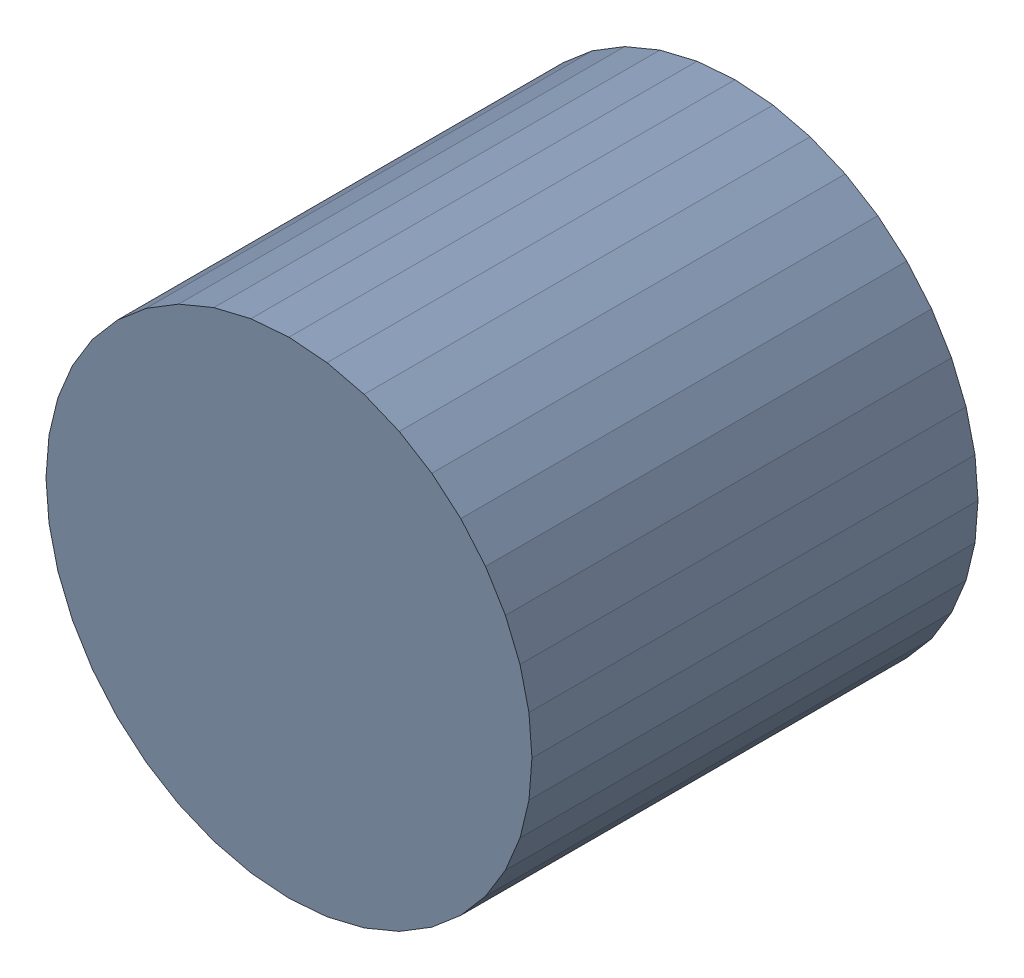
SolidWorks assembly C10_Motor_8Kanaloa_v2.0.0_Motor, configuration Default. Lengths in mm.
Overall size (6.32 6.32 5.8).
2 component instances, 1 part files, 0 mates.
Components (placement in the parent):
- 352892112-1: 352892112 [Default] at (131.568 127.127 0) size (6.32 6.32 5.8)
  - Extruded_11-1: Extruded_11 [Default] at origin size (6.32 6.32 5.8)
